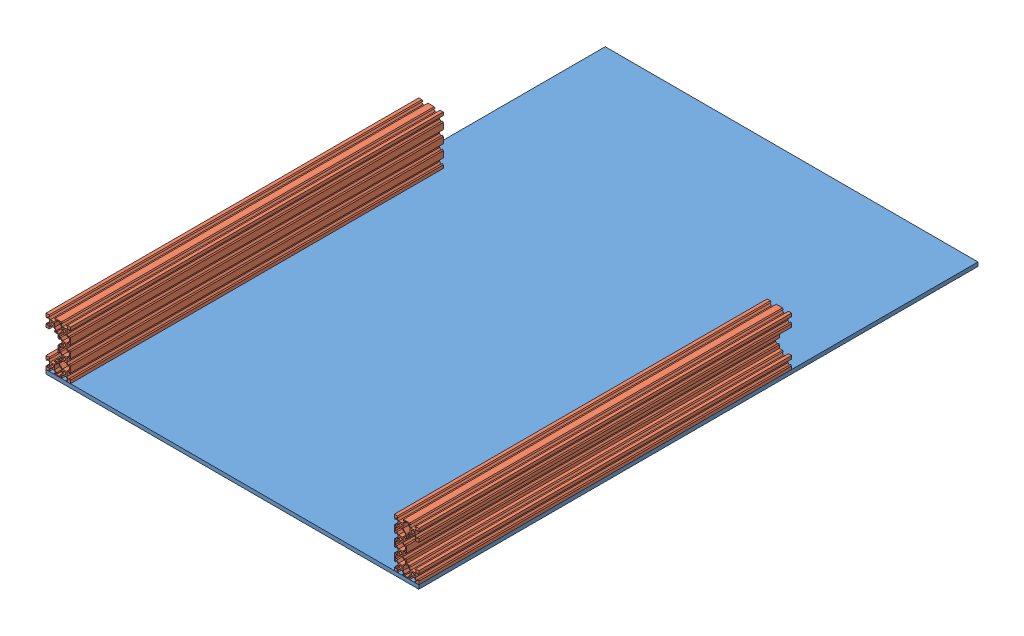
SolidWorks assembly Assem1, configuration Default. Lengths in mm.
Overall size (609.6 86.35 914.4).
3 component instances, 2 part files, 6 mates.
Components (placement in the parent):
- Plate-1: Plate [Default] at (359.6359 486.524 683.7132) size (609.6 6.35 914.4)
- Cbeam 3ft-1: Cbeam 3ft [Default] at (84.8359 532.874 531.3132) x (0 1 0) z (0 0 1) size (80 40 609.6)
- Cbeam 3ft-2: Cbeam 3ft [Default] at (634.4359 532.874 531.3132) x (0 -1 0) z (0 0 1) size (80 40 609.6)
Mates (geometry in assembly coordinates):
- Coincident1: coincident anti-aligned: plane of Plate-1 through (359.6359 492.874 683.7132) normal (0 1 0); plane of Cbeam 3ft-2 through (634.4359 492.874 1140.9132) normal (0 -1 0)
- Coincident2: coincident aligned: plane of Plate-1 through (664.4359 492.874 1140.9132) normal (0 0 1); plane of Cbeam 3ft-2 through (634.4359 532.874 1140.9132) normal (0 0 1)
- Coincident3: coincident aligned: plane of Plate-1 through (664.4359 492.874 226.5132) normal (1 0 0); plane of Cbeam 3ft-2 through (664.4359 532.874 1140.9132) normal (1 0 0)
- Coincident4: coincident anti-aligned: plane of Plate-1 through (359.6359 492.874 683.7132) normal (0 1 0); plane of Cbeam 3ft-1 through (84.8359 492.874 1140.9132) normal (0 -1 0)
- Coincident5: coincident aligned: plane of Plate-1 through (664.4359 492.874 1140.9132) normal (0 0 1); plane of Cbeam 3ft-1 through (84.8359 532.874 1140.9132) normal (0 0 1)
- Coincident6: coincident aligned: plane of Plate-1 through (54.8359 492.874 226.5132) normal (-1 0 0); plane of Cbeam 3ft-1 through (54.8359 532.874 1140.9132) normal (-1 0 0)
